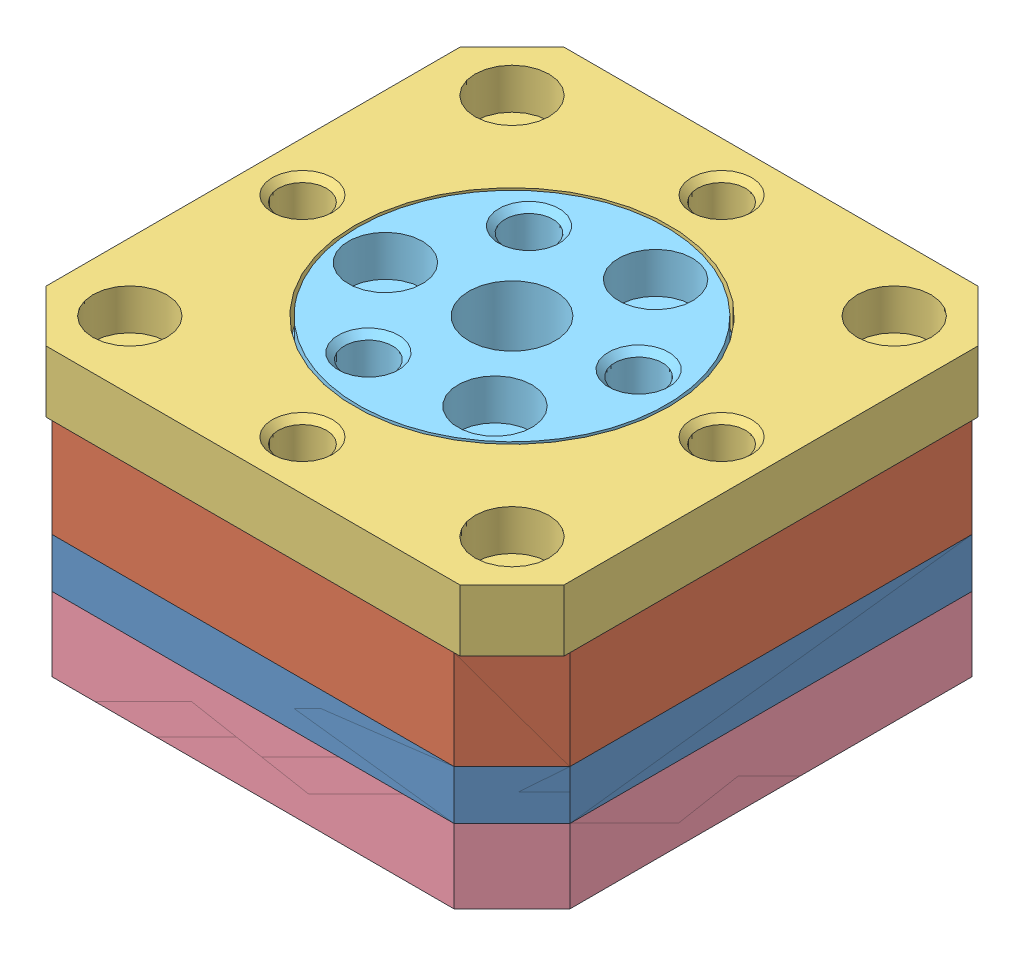
SolidWorks assembly 减速器, configuration 默认. Lengths in mm.
Overall size (42 23 42).
5 component instances, 5 part files, 14 mates.
Components (placement in the parent):
- 主壳 v1-2-1: 主壳 v1-2 [默认] at (0 -17 0) x (1 0 0) z (0 1 0) size (42 42 4)
- 谐波减速器-1: 谐波减速器 [默认] at (42 -5 0) x (-1 0 0) z (0 -1 0) size (42 42 10)
- 外壳-上部-1: 外壳-上部 [默认] at (42 0 -42) x (0 0 1) z (1 0 0) size (42 5 42)
- 主壳 v1-11-2: 主壳 v1-11 [默认] at (42 -23 -42) x (-1 0 0) z (0 1 0) size (42 42 8)
- 输出2-1: 输出2 [默认] at (21 -5 -21) x (0.626297 0 0.779585) z (-0.779585 0 0.626297) size (28 5 28)
Mates (geometry in assembly coordinates):
- 重合11: coincident anti-aligned: plane of 主壳 v1-2-1 through (0.3333 -13 -26.2998) normal (0 1 0); plane of 谐波减速器-1 through (41.6667 -13 -15.7002) normal (0 -1 0)
- 重合12: coincident aligned: plane of 主壳 v1-2-1 through (15.5621 -14.3333 0) normal (0 0 1); plane of 主壳 v1-11-2 through (26.4379 -19 0) normal (0 0 1)
- 重合13: coincident anti-aligned: plane of 主壳 v1-2-1 through (0.6667 -17 -15.5621) normal (0 -1 0); plane of 主壳 v1-11-2 through (38.7377 -17 -40.1046) normal (0 1 0)
- 重合14: coincident aligned: plane of 主壳 v1-2-1 through (0 -14.3333 -15.5621) normal (-1 0 0); plane of 主壳 v1-11-2 through (0 -21 -26.4379) normal (-1 0 0)
- 重合15: coincident aligned: plane of 谐波减速器-1 through (26.4379 -10.3333 0) normal (0 0 1); plane of 主壳 v1-11-2 through (26.4379 -19 0) normal (0 0 1)
- 重合16: coincident aligned: plane of 谐波减速器-1 through (0 -10.3333 -15.5621) normal (-1 0 0); plane of 主壳 v1-11-2 through (0 -21 -26.4379) normal (-1 0 0)
- 距离1: distance = 18 mm aligned: plane of 外壳-上部-1 through (42 -5 -42) normal (0 -1 0); plane of 主壳 v1-11-2 through (38.75 -23 -21) normal (0 -1 0)
- 同心1: concentric aligned: cylinder of 外壳-上部-1 through (21 -5 -21) axis (0 1 0) radius 12.75; cylinder of 主壳 v1-11-2 through (21 -23 -21) axis (0 1 0) radius 11.2493
- 重合18: coincident aligned: plane of 外壳-上部-1 through (42 -5 0) normal (0 0 1); plane of 主壳 v1-11-2 through (26.4379 -19 0) normal (0 0 1)
- 同心3: concentric anti-aligned: cylinder of 外壳-上部-1 through (21 -5 -21) axis (0 1 0) radius 12.75; cylinder of 输出2-1 through (21 0 -21) axis (0 -1 0) radius 12.5
- 重合19: coincident aligned: plane of 外壳-上部-1 through (42 0 -42) normal (0 1 0); plane of 输出2-1 through (21 0 -21) normal (0 1 0)
- 重合20: coincident aligned: plane of 外壳-上部-1 through (42 0 -42) normal (0 1 0)
- 重合21: coincident aligned: plane of 外壳-上部-1 through (42 -5 0) normal (0 0 1)
- 重合22: coincident anti-aligned: plane of 外壳-上部-1 through (0 -5 -42) normal (-1 0 0)
